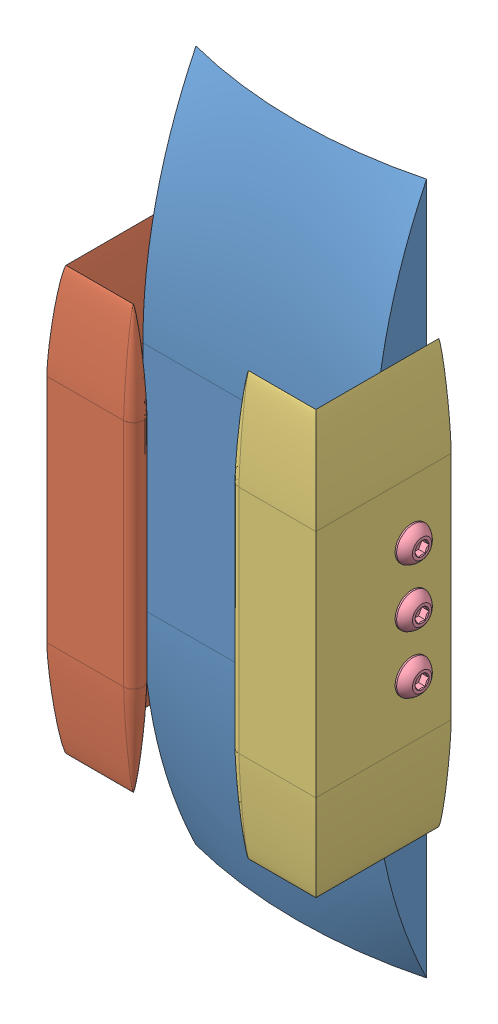
SolidWorks assembly 10007-R02_LAUNCH_LUG, configuration Default. Lengths in mm.
Overall size (96.06 228.6 46.28).
9 component instances, 4 part files, 12 mates.
Components (placement in the parent):
- 14031-R02_LAUNCH_LUG_FACE-2: 14031-R02_LAUNCH_LUG_FACE [Default] at origin size (76.36 228.6 22.35)
- 14040-R02_LAUNCH_LUG_LEFT-1: 14040-R02_LAUNCH_LUG_LEFT [Default] at origin size (29.52 139.7 46.08)
- 14039-R02_LAUNCH_LUG_RIGHT-2: 14039-R02_LAUNCH_LUG_RIGHT [Default] at origin size (29.52 139.7 46.08)
- 92949A542_18-8 SS BUTTON-HEAD SOCKET CAP SCREW-1: 92949A542_18-8 SS BUTTON-HEAD SOCKET CAP SCREW [92949A542] at (-47.8028 57.15 -6.35) x (0 1 0) z (-1 0 0) size (11.1 11.1 29.48)
- 92949A542_18-8 SS BUTTON-HEAD SOCKET CAP SCREW-2: 92949A542_18-8 SS BUTTON-HEAD SOCKET CAP SCREW [92949A542] at (-47.8028 38.1 -6.35) x (0 1 0) z (-1 0 0) size (11.1 11.1 29.48)
- 92949A542_18-8 SS BUTTON-HEAD SOCKET CAP SCREW-3: 92949A542_18-8 SS BUTTON-HEAD SOCKET CAP SCREW [92949A542] at (-47.8028 19.05 -6.35) x (0 1 0) z (-1 0 0) size (11.1 11.1 29.48)
- 92949A542_18-8 SS BUTTON-HEAD SOCKET CAP SCREW-4: 92949A542_18-8 SS BUTTON-HEAD SOCKET CAP SCREW [92949A542] at (47.8028 57.15 -6.35) x (0 1 0) z (1 0 0) size (11.1 11.1 29.48)
- 92949A542_18-8 SS BUTTON-HEAD SOCKET CAP SCREW-5: 92949A542_18-8 SS BUTTON-HEAD SOCKET CAP SCREW [92949A542] at (47.8028 38.1 -6.35) x (0 1 0) z (1 0 0) size (11.1 11.1 29.48)
- 92949A542_18-8 SS BUTTON-HEAD SOCKET CAP SCREW-6: 92949A542_18-8 SS BUTTON-HEAD SOCKET CAP SCREW [92949A542] at (47.8028 19.05 -6.35) x (0 1 0) z (1 0 0) size (11.1 11.1 29.48)
Mates (geometry in assembly coordinates):
- Coincident1: coincident: plane of 14031-R02_LAUNCH_LUG_FACE-2 through (0 0 0) normal (0 0 1); plane of assembly through (0 0 0) normal (0 0 1)
- Coincident3: coincident: plane of 14031-R02_LAUNCH_LUG_FACE-2 through (0 0 0) normal (0 1 0); plane of assembly through (0 0 0) normal (0 1 0)
- Coincident4: coincident: plane of 14031-R02_LAUNCH_LUG_FACE-2 through (0 0 0) normal (1 0 0); plane of assembly through (0 0 0) normal (1 0 0)
- Concentric1: concentric: circle of 14040-R02_LAUNCH_LUG_LEFT-1; circle of 14031-R02_LAUNCH_LUG_FACE-2
- Coincident6: coincident: plane of 14040-R02_LAUNCH_LUG_LEFT-1 through (-38.1 76.2 -17.5393) normal (1 0 0); plane of 14031-R02_LAUNCH_LUG_FACE-2 through (-38.1 76.2 0) normal (-1 0 0)
- Concentric2: concentric: circle of 14031-R02_LAUNCH_LUG_FACE-2; circle of 14039-R02_LAUNCH_LUG_RIGHT-2
- Coincident8: coincident: plane of 14031-R02_LAUNCH_LUG_FACE-2 through (38.1 76.2 0) normal (1 0 0); plane of 14039-R02_LAUNCH_LUG_RIGHT-2 through (38.1 76.2 -17.5393) normal (-1 0 0)
- Concentric3: concentric: circle of 14031-R02_LAUNCH_LUG_FACE-2; circle of 14040-R02_LAUNCH_LUG_LEFT-1
- Concentric4: concentric: circle of 14031-R02_LAUNCH_LUG_FACE-2; circle of 14039-R02_LAUNCH_LUG_RIGHT-2
- Coincident10: coincident: plane of 14040-R02_LAUNCH_LUG_LEFT-1 through (-44.45 76.2 25.4) normal (-1 0 0); plane of 92949A542_18-8 SS BUTTON-HEAD SOCKET CAP SCREW-1 through (-44.45 57.15 -0.8001) normal (1 0 0)
- Concentric5: concentric: circle of 14040-R02_LAUNCH_LUG_LEFT-1; circle of 92949A542_18-8 SS BUTTON-HEAD SOCKET CAP SCREW-1
- Parallel1: parallel: plane of 92949A542_18-8 SS BUTTON-HEAD SOCKET CAP SCREW-1 through (-47.8028 57.15 -6.35) normal (0 0 -1); plane of assembly through (0 0 0) normal (0 0 1)
